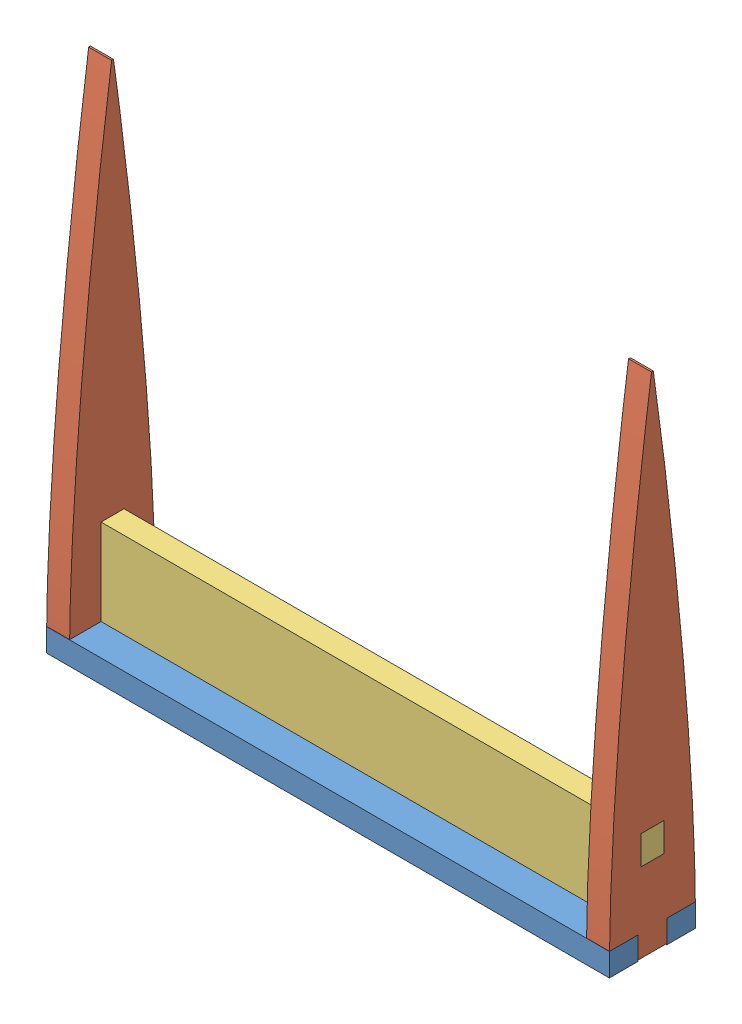
SolidWorks assembly Assem2, configuration Default. Lengths in mm.
Overall size (124.46 158.81 19.05).
4 component instances, 3 part files, 9 mates.
Components (placement in the parent):
- Keel_streamline_face-1: Keel_streamline_face [Default] at (-259.2982 -13.1588 120.7295) size (124.46 5.08 19.05)
- Keel_streamline_rib-1: Keel_streamline_rib [Default] at (-259.2982 -60.5298 111.2045) x (0 1 0) z (1 0 0) size (158.81 18.96 5.08)
- Keel_streamline_rib-2: Keel_streamline_rib [Default] at (-134.8382 -60.5298 111.2045) x (0 1 0) z (-1 0 0) size (158.81 18.96 5.08)
- Keel_streamline_support-1: Keel_streamline_support [Default] at (-254.2182 -8.0788 108.6645) x (1 0 0) z (0 -1 0) size (124.46 5.08 23.88)
Mates (geometry in assembly coordinates):
- Coincident1: coincident anti-aligned: plane of Keel_streamline_face-1 through (-200.2432 -13.1588 113.7445) normal (0 0 -1); plane of Keel_streamline_support-1 through (-281.2216 -8.0788 113.7445) normal (0 0 1)
- Coincident2: coincident anti-aligned: plane of Keel_streamline_face-1 through (-259.2982 -8.0788 120.7295) normal (0 1 0); plane of Keel_streamline_support-1 through (-281.2216 -8.0788 113.7445) normal (0 -1 0)
- Coincident4: coincident anti-aligned: plane of Keel_streamline_rib-1 through (-259.2982 42.9102 103.9086) normal (1 0 0); plane of Keel_streamline_support-1 through (-281.2216 -8.0788 113.7445) normal (-1 0 0)
- Coincident5: coincident anti-aligned: plane of Keel_streamline_rib-1 through (-259.2982 11.0884 107.9176) normal (0 -1 0); plane of Keel_streamline_support-1 through (-281.2216 10.9712 113.7445) normal (0 1 0)
- Coincident6: coincident anti-aligned: plane of Keel_streamline_rib-1 through (-259.2982 4.7384 107.9176) normal (0 0 1); plane of Keel_streamline_support-1 through (-281.2216 -8.0788 108.6645) normal (0 0 -1)
- Coincident7: coincident anti-aligned: plane of Keel_streamline_rib-2 through (-166.9216 42.793 117.7534) normal (-1 0 0); plane of Keel_streamline_support-1 through (-166.9216 -8.0788 113.7445) normal (1 0 0)
- Coincident8: coincident anti-aligned: plane of Keel_streamline_rib-2 through (-166.9216 4.6212 113.7445) normal (0 0 -1); plane of Keel_streamline_support-1 through (-281.2216 -8.0788 113.7445) normal (0 0 1)
- Coincident9: coincident anti-aligned: plane of Keel_streamline_rib-2 through (-166.9216 10.9712 113.7445) normal (0 -1 0); plane of Keel_streamline_support-1 through (-281.2216 10.9712 113.7445) normal (0 1 0)
- Coincident10: coincident anti-aligned: plane of Keel_streamline_face-1 through (-254.2182 -8.0788 108.0295) normal (-1 0 0); plane of Keel_streamline_rib-1 through (-254.2182 42.793 104.6555) normal (1 0 0)
